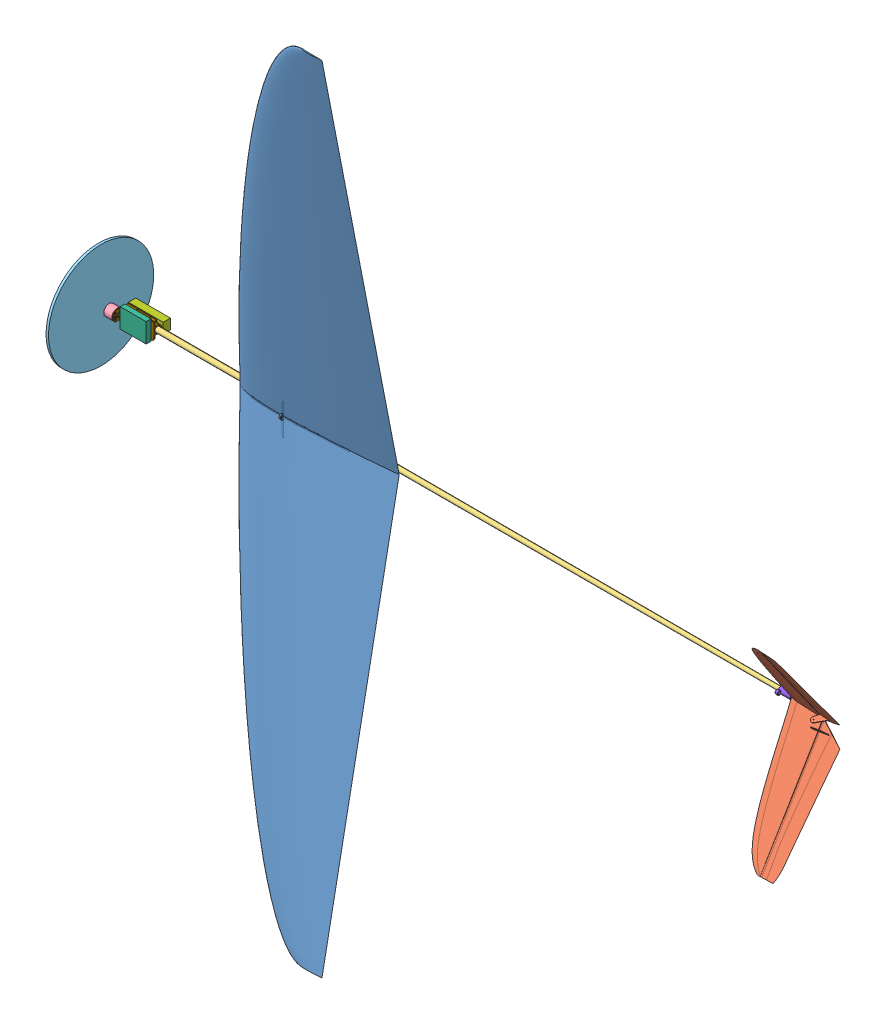
SolidWorks assembly feather-assembly, configuration Default. Lengths in mm.
Overall size (925.77 981.79 158.92).
9 component instances, 9 part files, 24 mates.
Components (placement in the parent):
- Wing-1: Wing [Default] at (0 0 6.171) size (196.05 981.79 108.12)
- VTail^feather-assembly-1: VTail^feather-assembly [Default] at (48.895 0 2) size (76.82 245.58 94.2) (virtual)
- Boom^feather-assembly-1: Boom^feather-assembly [Default] at origin size (826 6.74 6.74) (virtual)
- Motor-1: Motor [Default] at (-198.5062 0 8.9643) size (10 13.45 13.45)
- Prop-1: Prop [Default] at (-221.5062 0 8.9643) size (3 130 130)
- FC-1: FC [Default] at (-177.0466 0 4.8) size (32 24 6)
- Battery-1: Battery [Default] at (-177.0062 0 -13.8) size (43 12.5 9)
- VTail Mount^feather-assembly-1: VTail Mount^feather-assembly [Default] at origin size (39.98 15.84 12.35) (virtual)
- Motor Mount-1: Motor Mount [Default] at (-197.7062 0 0) size (41 20 19.95)
Mates (geometry in assembly coordinates):
- Coincident1: coincident aligned: plane of VTail^feather-assembly-1 through (48.895 0 2) normal (0 1 0)
- Distance1: distance = 2 mm aligned: plane of VTail^feather-assembly-1 through (48.895 0 2) normal (0 0 1)
- Coincident4: coincident aligned: plane of Wing-1 through (0 0 6.171) normal (1 0 0)
- Coincident6: coincident aligned: plane of Wing-1 through (0 0 6.171) normal (0 1 0)
- Concentric1: concentric anti-aligned: cylinder of Wing-1 through (-13.7366 0 0) axis (-1 0 0) radius 3.235; cone of Boom^feather-assembly-1 through (-198.5062 0 0) axis (1 0 0)
- Coincident7: coincident aligned: plane of FC Mount-1 through (-187.1763 0 3.6) normal (0 1 0)
- Coincident10: coincident: plane of Battery-1 through (-338.3437 6.25 14) normal (-1 0 0); line of Avionics Mount^feather-assembly-1 through (-191.7062 0.8 5) axis (0 -1 0)
- Coincident12: coincident aligned: plane of Battery-1 through (-177.0062 0 -13.8) normal (0 1 0)
- Coincident15: coincident anti-aligned: plane of FC-1 through (-177.0466 0 4.8) normal (0 0 -1); plane of Motor Mount-1 through (-197.7062 0 4.8) normal (0 0 1)
- Coincident17: coincident aligned: plane of FC Mount-1 through (-187.1763 0 3.6) normal (0 1 0)
- Coincident18: coincident aligned: plane of FC-1 through (-177.0466 0 4.8) normal (0 1 0)
- Coincident19: coincident anti-aligned: plane of VTail^feather-assembly-1 through (627.4938 0 2) normal (-1 0 0); plane of Boom^feather-assembly-1 through (627.4938 0 0) normal (1 0 0)
- Coincident20: coincident aligned: plane of Motor-1 through (-198.5062 0 8.9643) normal (0 1 0)
- Concentric3: concentric anti-aligned: cylinder of Motor-1 through (-208.5062 0 8.9643) axis (1 0 0) radius 6.725; cylinder of Prop-1 through (-218.5062 0 8.9643) axis (-1 0 0) radius 65
- Distance3: distance = 10 mm anti-aligned: plane of Prop-1 through (-218.5062 0 8.9643) normal (1 0 0); plane of Motor-1 through (-208.5062 0 8.9643) normal (-1 0 0)
- Concentric4: concentric aligned: cone of Boom^feather-assembly-1 through (-198.5062 0 0) axis (1 0 0); cylinder of FC Mount-1 through (-161.1763 0 0) axis (1 0 0) radius 3.6
- Concentric5: concentric aligned: cone of Boom^feather-assembly-1 through (-198.5062 0 0) axis (1 0 0); cylinder of Motor Mount-1 through (-198.5062 0 0) axis (1 0 0) radius 3.6
- Coincident23: coincident anti-aligned: circle of Boom^feather-assembly-1; plane of Motor Mount-1 through (-198.5062 3.182 5.7823) normal (-1 0 0)
- Coincident24: coincident aligned: plane of Motor Mount-1 through (-197.7062 0 0) normal (0 1 0)
- Concentric6: concentric anti-aligned: cylinder of Motor-1 through (-208.5062 0 8.9643) axis (1 0 0) radius 6.725; cylinder of Motor Mount-1 through (-197.0062 0 8.9643) axis (-1 0 0) radius 1.75
- Coincident25: coincident anti-aligned: plane of Motor-1 through (-198.5062 0 8.9643) normal (1 0 0); plane of Motor Mount-1 through (-198.5062 3.182 5.7823) normal (-1 0 0)
- Coincident26: coincident anti-aligned: plane of Battery-1 through (-177.0062 0 -4.8) normal (0 0 1); plane of Motor Mount-1 through (-197.7062 0 -4.8) normal (0 0 -1)
- Coincident27: coincident aligned: plane of Battery-1 through (-198.5062 6.25 -4.8) normal (-1 0 0); plane of Motor Mount-1 through (-198.5062 3.182 5.7823) normal (-1 0 0)
- Coincident28: coincident: plane of FC-1 through (-193.0466 12 10.8) normal (-1 0 0); line of Motor Mount-1 through (-193.0466 -1.1023 4.8) axis (0 1 0)
